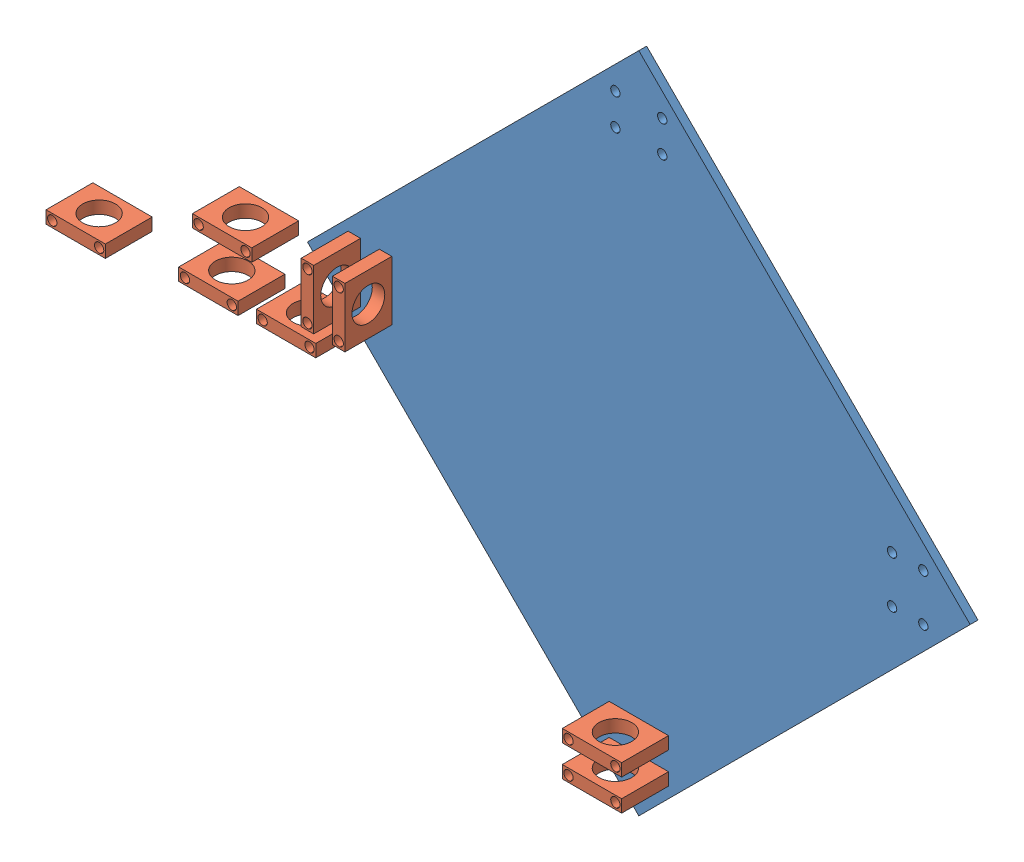
SolidWorks assembly Assem1, configuration Default. Lengths in mm.
Overall size (277.5 212.13 41.02).
9 component instances, 2 part files, 12 mates.
Components (placement in the parent):
- base-1: base [Default] at (53.6353 -20.886 192.4001) size (212.13 212.13 2.5)
- holder-1: holder [Default] at (-25.4307 75.68 209.9001) x (0 1 0) z (0 0 1) size (19 4 15)
- holder-2: holder [Default] at (-35.4307 75.68 209.9001) x (0 1 0) z (0 0 1) size (19 4 15)
- holder-3: holder [Default] at (-101.3496 45.9369 187.1909) size (19 4 15)
- holder-4: holder [Default] at (-71.2331 51.9031 192.4355) size (19 4 15)
- holder-5: holder [Default] at (-74.0378 85.838 210.1135) size (19 4 15)
- holder-6: holder [Default] at (-117.7986 66.569 213.2151) size (19 4 15)
- holder-7: holder [Default] at (44.1353 2.114 209.9001) size (19 4 15)
- holder-8: holder [Default] at (44.1353 -7.886 209.9001) size (19 4 15)
Mates (geometry in assembly coordinates):
- Concentric1: concentric: cylinder of base-1 through (-27.4307 77.68 194.9001) axis (0 0 -1) radius 1.5; cylinder of holder-1 through (-27.4307 77.68 194.9001) axis (0 0 1) radius 1.5
- Concentric2: concentric: cylinder of base-1 through (-27.4307 92.68 194.9001) axis (0 0 -1) radius 1.5; cylinder of holder-1 through (-27.4307 92.68 194.9001) axis (0 0 1) radius 1.5
- Coincident1: coincident: plane of base-1 through (53.6353 -20.886 194.9001) normal (0 0 1); plane of holder-1 through (-29.4307 75.68 194.9001) normal (0 0 -1)
- Concentric6: concentric: cylinder of base-1 through (-37.4307 92.68 194.9001) axis (0 0 -1) radius 1.5; cylinder of holder-2 through (-37.4307 92.68 194.9001) axis (0 0 1) radius 1.5
- Coincident2: coincident: plane of base-1 through (53.6353 -20.886 194.9001) normal (0 0 1); plane of holder-2 through (-39.4307 75.68 194.9001) normal (0 0 -1)
- Concentric7: concentric: cylinder of base-1 through (-37.4307 77.68 194.9001) axis (0 0 -1) radius 1.5; cylinder of holder-2 through (-37.4307 77.68 194.9001) axis (0 0 1) radius 1.5
- Concentric8: concentric: cylinder of base-1 through (61.1353 -5.886 194.9001) axis (0 0 -1) radius 1.5; cylinder of holder-8 through (61.1353 -5.886 194.9001) axis (0 0 1) radius 1.5
- Concentric9: concentric: cylinder of base-1 through (46.1353 -5.886 194.9001) axis (0 0 -1) radius 1.5; cylinder of holder-8 through (46.1353 -5.886 194.9001) axis (0 0 1) radius 1.5
- Coincident4: coincident: plane of base-1 through (53.6353 -20.886 194.9001) normal (0 0 1); plane of holder-8 through (44.1353 -3.886 194.9001) normal (0 0 -1)
- Concentric10: concentric: cylinder of base-1 through (61.1353 4.114 194.9001) axis (0 0 -1) radius 1.5; cylinder of holder-7 through (61.1353 4.114 177.4001) axis (0 0 1) radius 1.5
- Concentric11: concentric: cylinder of base-1 through (46.1353 4.114 194.9001) axis (0 0 -1) radius 1.5; cylinder of holder-7 through (46.1353 4.114 177.4001) axis (0 0 1) radius 1.5
- Coincident5: coincident: plane of base-1 through (53.6353 -20.886 194.9001) normal (0 0 1); plane of holder-7 through (44.1353 6.114 194.9001) normal (0 0 -1)
